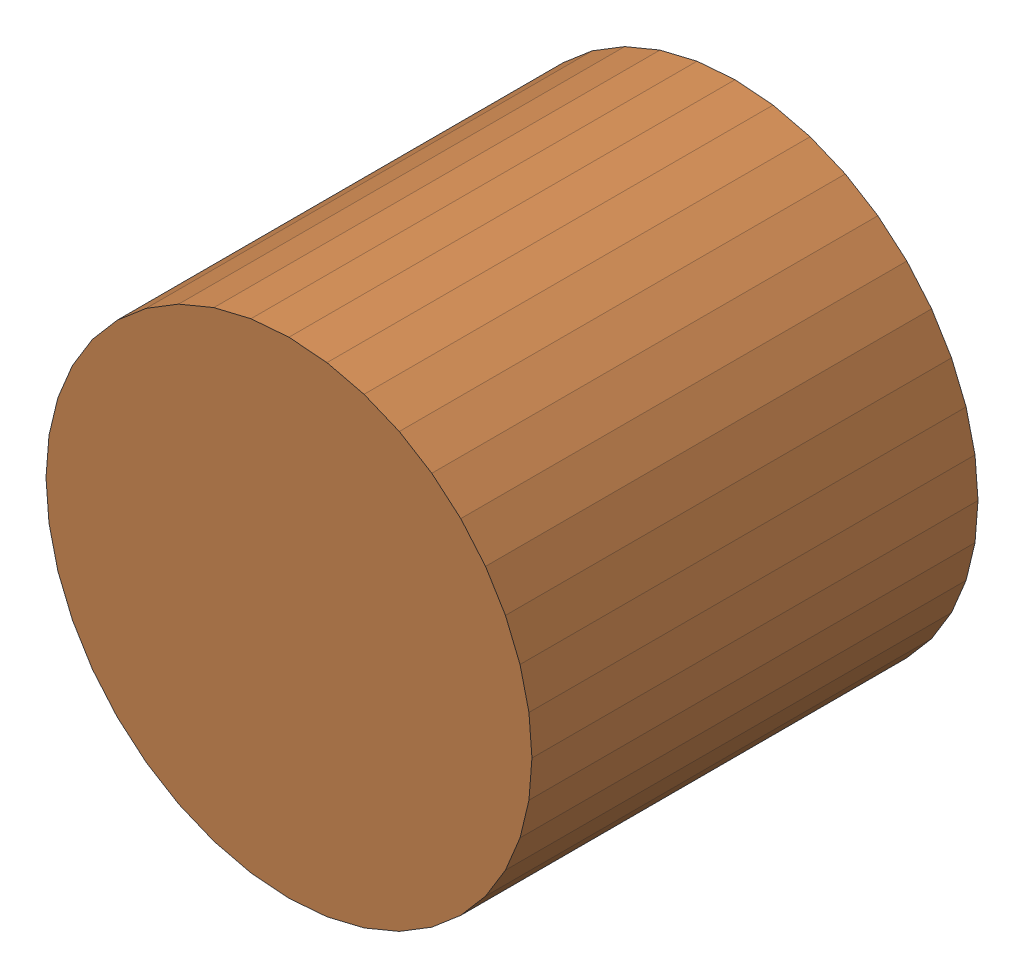
SolidWorks assembly LED1Kanaloa_v2.0.0_Motor, configuration Default. Lengths in mm.
Overall size (6.32 6.32 5.8).
4 component instances, 2 part files, 0 mates.
Components (placement in the parent):
- 334788912-1: 334788912 [Default] at (56.134 111.8257 0) size (1.15 1.38 0.8)
  - Extruded_31-1: Extruded_31 [Default] at origin size (1.15 1.38 0.8)
- 334789296-1: 334789296 [Default] at (56.134 111.8382 0) size (6.32 6.32 5.8)
  - Extruded_11-1: Extruded_11 [Default] at origin size (6.32 6.32 5.8)
